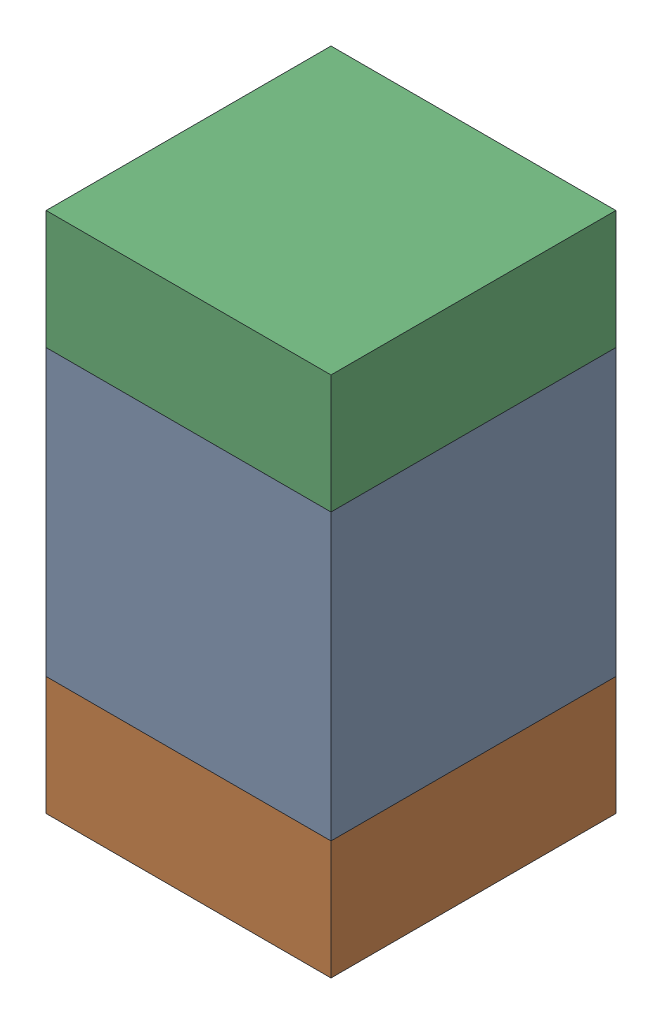
SolidWorks assembly C600_2PCB, configuration Default. Lengths in mm.
Overall size (0.6 1.1 0.6).
6 component instances, 2 part files, 0 mates.
Components (placement in the parent):
- 761606048-1: 761606048 [Default] at (99.8 103.6 -2.2638) size (0.6 0.6 0.6)
  - Extruded_9-1: Extruded_9 [Default] at origin size (0.6 0.6 0.6)
- 854785296-1: 854785296 [Default] at (99.8 103.175 -2.2638) size (0.6 0.25 0.6)
  - Extruded_10-1: Extruded_10 [Default] at origin size (0.6 0.25 0.6)
- 854785296-2: 854785296 [Default] at (99.8 104.025 -2.2638) size (0.6 0.25 0.6)
  - Extruded_10-1: Extruded_10 [Default] at origin size (0.6 0.25 0.6)
